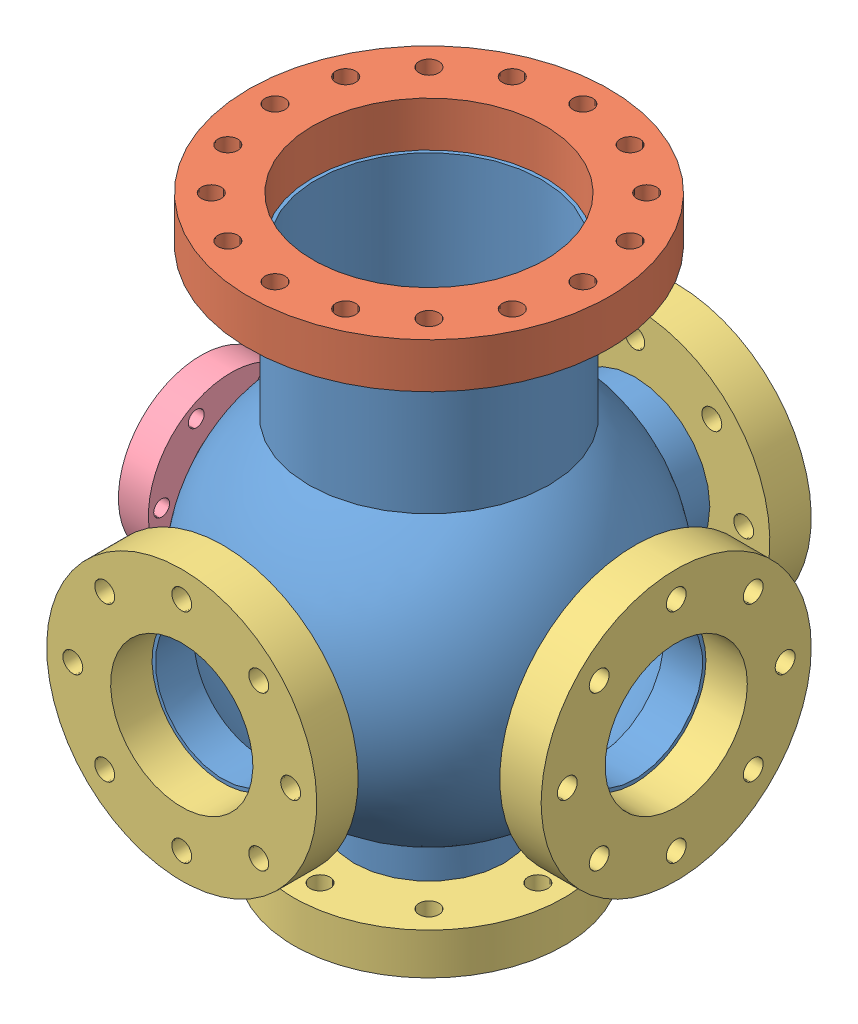
SolidWorks assembly custom_sixway_cross, configuration Default. Lengths in mm.
Overall size (201.17 247.4 209.3).
7 component instances, 4 part files, 12 mates.
Components (placement in the parent):
- custom_sixway_tube-1: custom_sixway_tube [Default] at (-1.4041 14.3928 -9.0374) size (170.94 210.82 174.24)
- 6in_CF_flange-3: 6in_CF_flange [Default] at (-1.4041 157.1408 -9.0374) x (1 0 0) z (0 -1 0) size (152.4 152.4 19.05)
- 4.5in_CF_flange-1: 4.5in_CF_flange [Default] at (85.7179 14.3928 -9.0374) x (0 -1 0) z (0 0 1) size (114.3 17.53 114.3)
- 4.5in_CF_flange-2: 4.5in_CF_flange [Default] at (-1.4041 14.3928 78.0846) x (1 0 0) z (0 -1 0) size (114.3 17.53 114.3)
- 4.5in_CF_flange-3: 4.5in_CF_flange [Default] at (-1.4041 14.3928 -113.6854) x (1 0 0) z (0 -1 0) size (114.3 17.53 114.3)
- 2.75in_CF_flange-1: 2.75in_CF_flange [Default] at (-97.9241 14.3928 -9.0374) x (0 -1 0) z (0 0 1) size (69.85 12.7 69.85)
- 4.5in_CF_flange-4: 4.5in_CF_flange [Default] at (-1.4041 -90.2552 -9.0374) size (114.3 17.53 114.3)
Mates (geometry in assembly coordinates):
- Coincident9: coincident anti-aligned: plane of custom_sixway_tube-1 through (-1.4041 138.0908 -9.0374) normal (0 1 0); plane of 6in_CF_flange-3 through (-1.4041 138.0908 -9.0374) normal (0 -1 0)
- Coincident10: coincident: line of custom_sixway_tube-1 through (-1.4041 -985.6072 -9.0374) axis (0 1 0); point of 6in_CF_flange-3
- Coincident14: coincident anti-aligned: plane of custom_sixway_tube-1 through (85.7179 14.3928 -9.0374) normal (1 0 0); plane of 4.5in_CF_flange-1 through (85.7179 14.3928 -9.0374) normal (-1 0 0)
- Coincident15: coincident: line of custom_sixway_tube-1 through (-1039.6767 14.3928 -9.0374) axis (1 0 0); point of 4.5in_CF_flange-1
- Coincident16: coincident anti-aligned: plane of custom_sixway_tube-1 through (-1.4041 14.3928 78.0846) normal (0 0 1); plane of 4.5in_CF_flange-2 through (-1.4041 14.3928 78.0846) normal (0 0 -1)
- Coincident17: coincident: line of custom_sixway_tube-1 through (-1.4041 14.3928 925.3663) axis (0 0 -1); point of 4.5in_CF_flange-2
- Coincident18: coincident anti-aligned: plane of custom_sixway_tube-1 through (-1.4041 14.3928 -96.1594) normal (0 0 -1); plane of 4.5in_CF_flange-3 through (-1.4041 14.3928 -96.1594) normal (0 0 1)
- Coincident19: coincident: line of custom_sixway_tube-1 through (-1.4041 14.3928 925.3663) axis (0 0 -1); point of 4.5in_CF_flange-3
- Coincident20: coincident anti-aligned: plane of custom_sixway_tube-1 through (-85.2241 14.3928 -9.0374) normal (-1 0 0); plane of 2.75in_CF_flange-1 through (-85.2241 14.3928 -9.0374) normal (1 0 0)
- Coincident21: coincident: line of custom_sixway_tube-1 through (-1039.6767 14.3928 -9.0374) axis (1 0 0); point of 2.75in_CF_flange-1
- Coincident22: coincident anti-aligned: plane of custom_sixway_tube-1 through (-1.4041 -72.7292 -9.0374) normal (0 -1 0); plane of 4.5in_CF_flange-4 through (-1.4041 -72.7292 -9.0374) normal (0 1 0)
- Coincident23: coincident: line of custom_sixway_tube-1 through (-1.4041 -985.6072 -9.0374) axis (0 1 0); point of 4.5in_CF_flange-4
